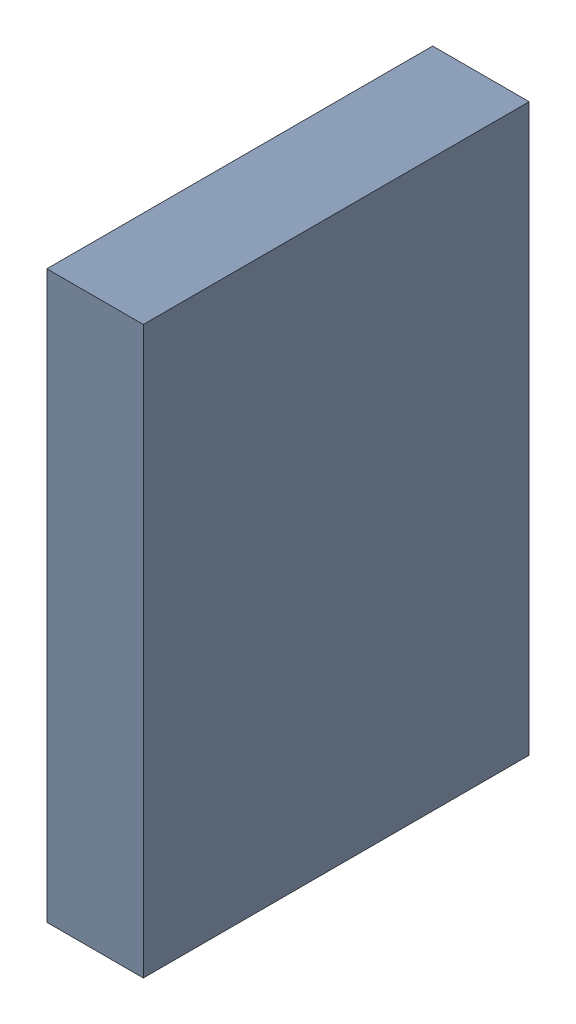
SolidWorks assembly D1, configuration Default. Lengths in mm.
Overall size (0.75 4.4 3).
6 component instances, 1 part files, 0 mates.
Components (placement in the parent):
- 6701982208-1: 6701982208 [Default] at (27.7 14.8 0) (suppressed, hidden)
- 6327400192-1: 6327400192 [Default] at (3.4667 5.07 -3.0378) x (0 0 -1) z (1 0 0)
  - 6701982208-1: 6701982208 [Default] at (27.7 14.8 0) (suppressed, hidden)
- 6327400384-1: 6327400384 [Default] at (3.7327 6.07 -2.0761) x (0 0 -1) z (1 0 0) size (3 4.4 0.75)
  - 6701982208-1: 6701982208 [Default] at (27.7 14.8 0) (suppressed, hidden)
  - Extruded-23-1: Extruded-23 [Default] at origin size (3 4.4 0.75)
